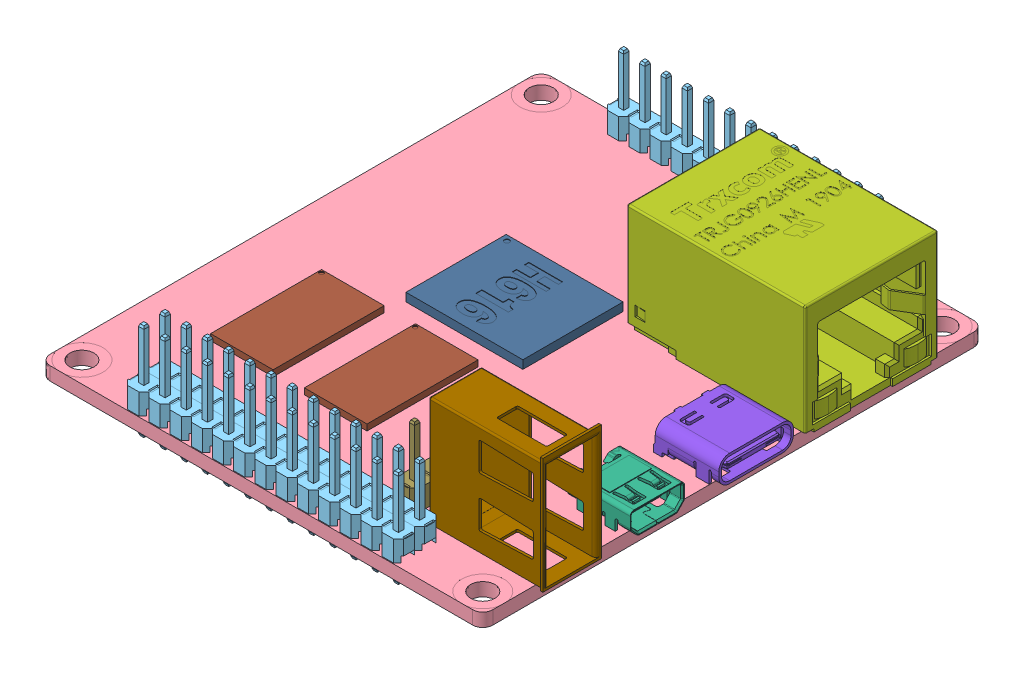
SolidWorks assembly OrangePi_Zero2, configuration 默认. Lengths in mm.
Overall size (54.2 18.1 60).
16 component instances, 12 part files, 37 mates.
Components (placement in the parent):
- Card slot assembly_Domyslna^OrangePi_Zero2-1: Card slot assembly_Domyslna^OrangePi_Zero2 [默认] at (-29.7448 -12.71 -17.6643) x (0 0 -1) z (0 1 0) size (11.95 11.4 1.48) (virtual)
  - card slot part 2 metal pin_Domyslna^Card slot assembly_Domyslna_OrangePi_Zero2-1: card slot part 2 metal pin_Domyslna^Card slot assembly_Domyslna_OrangePi_Zero2 [默认] at (-3.5293 -7.6678 12.2938) x (0 -1 0) z (1 0 0) size (7.95 0.89 8.04) (virtual)
  - sd card slot v1_Domyslna^Card slot assembly_Domyslna_OrangePi_Zero2-1: sd card slot v1_Domyslna^Card slot assembly_Domyslna_OrangePi_Zero2 [默认] at (-18.1743 -9.7848 12.71) x (-1 0 0) z (0 0 -1) size (11.71 10.28 1.3) (virtual)
  - part 3 v1_Domyslna^Card slot assembly_Domyslna_OrangePi_Zero2-1: part 3 v1_Domyslna^Card slot assembly_Domyslna_OrangePi_Zero2 [默认] at (-6.4643 -9.3448 11.38) x (1 0 0) z (0 0 -1) size (11.95 11.4 1.45) (virtual)
- pcb^OrangePi_Zero2-1: pcb^OrangePi_Zero2 [默认] at origin size (53 1.6 60) (virtual)
- PLS-13.step^OrangePi_Zero2-1: PLS-13.step^OrangePi_Zero2 [默认] at (-15.45 1.6 26.09) x (1 0 0) z (0 1 0) size (33.02 2.54 11.6) (virtual)
- PLS-13.step^OrangePi_Zero2-2: PLS-13.step^OrangePi_Zero2 [默认] at (-15.45 1.6 28.63) x (1 0 0) z (0 1 0) size (33.02 2.54 11.6) (virtual)
- PLS-13.step^OrangePi_Zero2-3: PLS-13.step^OrangePi_Zero2 [默认] at (-15.25 1.6 -28.63) x (1 0 0) z (0 1 0) size (33.02 2.54 11.6) (virtual)
- 11.0 Female micro HDMI connector_Domyslna^OrangePi_Zero2-1: 11.0 Female micro HDMI connector_Domyslna^OrangePi_Zero2 [默认] at (20 3.05 10.09) x (0 0 -1) z (1 0 0) size (6.5 3.51 7.5) (virtual)
- 12.0 Gigabit ethernet port raspberry^OrangePi_Zero2-1: 12.0 Gigabit ethernet port raspberry^OrangePi_Zero2 [默认] at (27.3 8.525 -15.75) x (0 0 -1) z (1 0 0) size (16.1 17.2 21.45) (virtual)
- 10.0 Female USB connector_Domyslna^OrangePi_Zero2-1: 10.0 Female USB connector_Domyslna^OrangePi_Zero2 [默认] at (19.99 3.18 -1.63) x (0 0 -1) z (1 0 0) size (8.94 3.96 7.9) (virtual)
- USB-A 111 (vertical on plate)___ _________^OrangePi_Zero2-1: USB-A 111 (vertical on plate)___ _________^OrangePi_Zero2 [默认] at (13.7 8.1368 23.65) x (1 0 0) z (0 1 0) size (14 9.14 18.1) (virtual)
- H616^OrangePi_Zero2-1: H616^OrangePi_Zero2 [默认] at (-3.5 1.72 -3.8) x (0 0 1) z (-1 0 0) size (12 1.12 14) (virtual)
- DDR3^OrangePi_Zero2-1: DDR3^OrangePi_Zero2 [默认] at (-14.25 1.9 11.45) size (7.5 1.03 13.3) (virtual)
- DDR3^OrangePi_Zero2-2: DDR3^OrangePi_Zero2 [默认] at (-3.01 1.9 11.45) size (7.5 1.03 13.3) (virtual)
- PLS-4^OrangePi_Zero2-1: PLS-4^OrangePi_Zero2 [默认] at (10.73 1.6 17.31) x (0 0 1) z (0 1 0) size (7.62 2.54 11.6) (virtual)
Mates (geometry in assembly coordinates):
- 重合1: coincident anti-aligned: plane of pcb^OrangePi_Zero2-1 through (0 1.6 0) normal (0 1 0); plane of 12.0 Gigabit ethernet port raspberry^OrangePi_Zero2-1 through (27.3 1.6 -15.75) normal (0 -1 0)
- 距离1: distance = 0.8 mm aligned: plane of 12.0 Gigabit ethernet port raspberry^OrangePi_Zero2-1 through (27.3 8.525 -15.75) normal (1 0 0); plane of pcb^OrangePi_Zero2-1 through (26.5 1.6 -30) normal (1 0 0)
- 距离2: distance = 6.3 mm aligned: plane of pcb^OrangePi_Zero2-1 through (27.25 1.4 -30) normal (0 0 -1); plane of 12.0 Gigabit ethernet port raspberry^OrangePi_Zero2-1 through (5.95 1.95 -23.7) normal (0 0 -1)
- 重合2: coincident anti-aligned: plane of pcb^OrangePi_Zero2-1 through (0 1.6 0) normal (0 1 0); plane of 10.0 Female USB connector_Domyslna^OrangePi_Zero2-1 through (27.6 1.6 1.54) normal (0 -1 0)
- 距离3: distance = 1.1 mm aligned: plane of 10.0 Female USB connector_Domyslna^OrangePi_Zero2-1 through (27.6 3.46 1.54) normal (1 0 0); plane of pcb^OrangePi_Zero2-1 through (26.5 1.6 -30) normal (1 0 0)
- 距离4: distance = 23.9 mm aligned: plane of pcb^OrangePi_Zero2-1 through (27.25 1.4 -30) normal (0 0 -1); plane of 10.0 Female USB connector_Domyslna^OrangePi_Zero2-1 through (27.6 2.9 -6.1) normal (0 0 -1)
- 重合4: coincident anti-aligned: plane of pcb^OrangePi_Zero2-1 through (0 1.6 0) normal (0 1 0); plane of 11.0 Female micro HDMI connector_Domyslna^OrangePi_Zero2-1 through (22 1.6 8.2221) normal (0 -1 0)
- 重合5: coincident anti-aligned: plane of pcb^OrangePi_Zero2-1 through (0 1.6 0) normal (0 1 0); plane of 11.0 Female micro HDMI connector_Domyslna^OrangePi_Zero2-1 through (22 1.6 8.2221) normal (0 -1 0)
- 距离5: distance = 1 mm aligned: plane of 11.0 Female micro HDMI connector_Domyslna^OrangePi_Zero2-1 through (27.5 2.05 12.2455) normal (1 0 0); plane of pcb^OrangePi_Zero2-1 through (26.5 1.6 -30) normal (1 0 0)
- 距离6: distance = 4 mm anti-aligned: plane of 10.0 Female USB connector_Domyslna^OrangePi_Zero2-1 through (27.6 3.46 2.84) normal (0 0 1); plane of 11.0 Female micro HDMI connector_Domyslna^OrangePi_Zero2-1 through (27.5 2.7298 6.84) normal (0 0 -1)
- 重合7: coincident anti-aligned: plane of pcb^OrangePi_Zero2-1 through (0 1.6 0) normal (0 1 0); plane of USB-A 111 (vertical on plate)___ _________^OrangePi_Zero2-1 through (17.9 1.6 16) normal (0 -1 0)
- 距离7: distance = 1.2 mm aligned: plane of USB-A 111 (vertical on plate)___ _________^OrangePi_Zero2-1 through (27.7 1.5868 17.35) normal (1 0 0); plane of pcb^OrangePi_Zero2-1 through (26.5 1.6 -30) normal (1 0 0)
- 距离8: distance = 6.35 mm aligned: plane of USB-A 111 (vertical on plate)___ _________^OrangePi_Zero2-1 through (13.7 1.5868 23.65) normal (0 0 1); plane of pcb^OrangePi_Zero2-1 through (27.25 1.4 30) normal (0 0 1)
- 重合8: coincident anti-aligned: plane of Card slot assembly_Domyslna^OrangePi_Zero2-1/sd card slot v1_Domyslna^Card slot assembly_Domyslna_OrangePi_Zero2-1 through (-24.6 0 -5.98) normal (0 1 0); plane of pcb^OrangePi_Zero2-1 through (0 0 0) normal (0 -1 0)
- 距离9: distance = 0.4 mm aligned: plane of Card slot assembly_Domyslna^OrangePi_Zero2-1/part 3 v1_Domyslna^Card slot assembly_Domyslna_OrangePi_Zero2-1 through (-26.1 -1.45 -17.175) normal (-1 0 0); plane of pcb^OrangePi_Zero2-1 through (-26.5 1.6 -30) normal (-1 0 0)
- 距离11: distance = 12.825 mm aligned: plane of Card slot assembly_Domyslna^OrangePi_Zero2-1/part 3 v1_Domyslna^Card slot assembly_Domyslna_OrangePi_Zero2-1 through (-26.1 -1.45 -17.175) normal (0 0 -1); plane of pcb^OrangePi_Zero2-1 through (27.25 1.4 -30) normal (0 0 -1)
- 重合11: coincident anti-aligned: plane of pcb^OrangePi_Zero2-1 through (0 1.6 0) normal (0 1 0); plane of PLS-13.step^OrangePi_Zero2-3 through (-12.71 1.6 -28.63) normal (0 -1 0)
- 重合13: coincident aligned: plane of PLS-13.step^OrangePi_Zero2-1 through (-12.91 1.6 26.09) normal (0 -1 0); plane of PLS-13.step^OrangePi_Zero2-2 through (-12.91 1.6 28.63) normal (0 -1 0)
- 重合14: coincident anti-aligned: plane of PLS-13.step^OrangePi_Zero2-1 through (14.36 1.6 27.36) normal (0 0 1); plane of PLS-13.step^OrangePi_Zero2-2 through (15.7 1.6 27.36) normal (0 0 -1)
- 重合15: coincident aligned: plane of PLS-13.step^OrangePi_Zero2-1 through (16.3 1.6 26.76) normal (1 0 0); plane of PLS-13.step^OrangePi_Zero2-2 through (16.3 1.6 29.3) normal (1 0 0)
- 重合16: coincident anti-aligned: plane of pcb^OrangePi_Zero2-1 through (0 1.6 0) normal (0 1 0); plane of PLS-13.step^OrangePi_Zero2-2 through (-12.91 1.6 28.63) normal (0 -1 0)
- 对称1: symmetric aligned: plane of PLS-13.step^OrangePi_Zero2-2 through (14.36 1.6 29.9) normal (0 0 1); plane of PLS-13.step^OrangePi_Zero2-3 through (15.9 1.6 -29.9) normal (0 0 -1); plane of assembly through (0 0 0) normal (0 0 1)
- 距离12: distance = 59.8 mm anti-aligned: plane of PLS-13.step^OrangePi_Zero2-3 through (15.9 1.6 -29.9) normal (0 0 -1); plane of PLS-13.step^OrangePi_Zero2-2 through (14.36 1.6 29.9) normal (0 0 1)
- 距离13: distance = 10 mm aligned: plane of PLS-13.step^OrangePi_Zero2-3 through (16.5 1.6 -27.96) normal (1 0 0); plane of pcb^OrangePi_Zero2-1 through (26.5 1.6 -30) normal (1 0 0)
- 距离14: distance = 10.2 mm aligned: plane of pcb^OrangePi_Zero2-1 through (26.5 1.6 -30) normal (1 0 0); plane of PLS-13.step^OrangePi_Zero2-2 through (16.3 1.6 29.3) normal (1 0 0)
- 重合17: coincident anti-aligned: plane of pcb^OrangePi_Zero2-1 through (0 1.6 0) normal (0 1 0); plane of PLS-4^OrangePi_Zero2-1 through (10.73 1.6 19.85) normal (0 -1 0)
- 距离15: distance = 6.34 mm aligned: plane of PLS-4^OrangePi_Zero2-1 through (9.46 -1.4 23.66) normal (0 0 1); plane of pcb^OrangePi_Zero2-1 through (27.25 1.4 30) normal (0 0 1)
- 距离16: distance = 14.5 mm aligned: plane of pcb^OrangePi_Zero2-1 through (26.5 1.6 -30) normal (1 0 0); plane of PLS-4^OrangePi_Zero2-1 through (12 1.6 17.98) normal (1 0 0)
- 重合18: coincident anti-aligned: plane of pcb^OrangePi_Zero2-1 through (0 1.6 0) normal (0 1 0); plane of DDR3^OrangePi_Zero2-1 through (-17.445 1.6 17.45) normal (0 -1 0)
- 重合19: coincident aligned: plane of DDR3^OrangePi_Zero2-1 through (-14.25 2.63 11.45) normal (0 1 0); plane of DDR3^OrangePi_Zero2-2 through (-3.01 2.63 11.45) normal (0 1 0)
- 重合20: coincident aligned: plane of DDR3^OrangePi_Zero2-1 through (-10.5 2.63 4.8) normal (0 0 -1); plane of DDR3^OrangePi_Zero2-2 through (0.74 2.63 4.8) normal (0 0 -1)
- 距离17: distance = 3.74 mm anti-aligned: plane of DDR3^OrangePi_Zero2-2 through (-6.76 2.63 18.1) normal (-1 0 0); plane of DDR3^OrangePi_Zero2-1 through (-10.5 2.63 18.1) normal (1 0 0)
- 距离18: distance = 8.5 mm aligned: plane of DDR3^OrangePi_Zero2-1 through (-18 2.63 18.1) normal (-1 0 0); plane of pcb^OrangePi_Zero2-1 through (-26.5 1.6 -30) normal (-1 0 0)
- 距离19: distance = 11.9 mm aligned: plane of DDR3^OrangePi_Zero2-1 through (-10.5 2.63 18.1) normal (0 0 1); plane of pcb^OrangePi_Zero2-1 through (27.25 1.4 30) normal (0 0 1)
- 重合24: coincident anti-aligned: plane of pcb^OrangePi_Zero2-1 through (0 1.6 0) normal (0 1 0); plane of H616^OrangePi_Zero2-1 through (-9.975 1.6 1.7) normal (0 -1 0)
- 距离20: distance = 16 mm aligned: plane of H616^OrangePi_Zero2-1 through (-10.5 2.72 2.2) normal (-1 0 0); plane of pcb^OrangePi_Zero2-1 through (-26.5 1.6 -30) normal (-1 0 0)
- 距离21: distance = 2.6 mm anti-aligned: plane of H616^OrangePi_Zero2-1 through (-10.5 2.72 2.2) normal (0 0 1); plane of DDR3^OrangePi_Zero2-1 through (-10.5 2.63 4.8) normal (0 0 -1)
